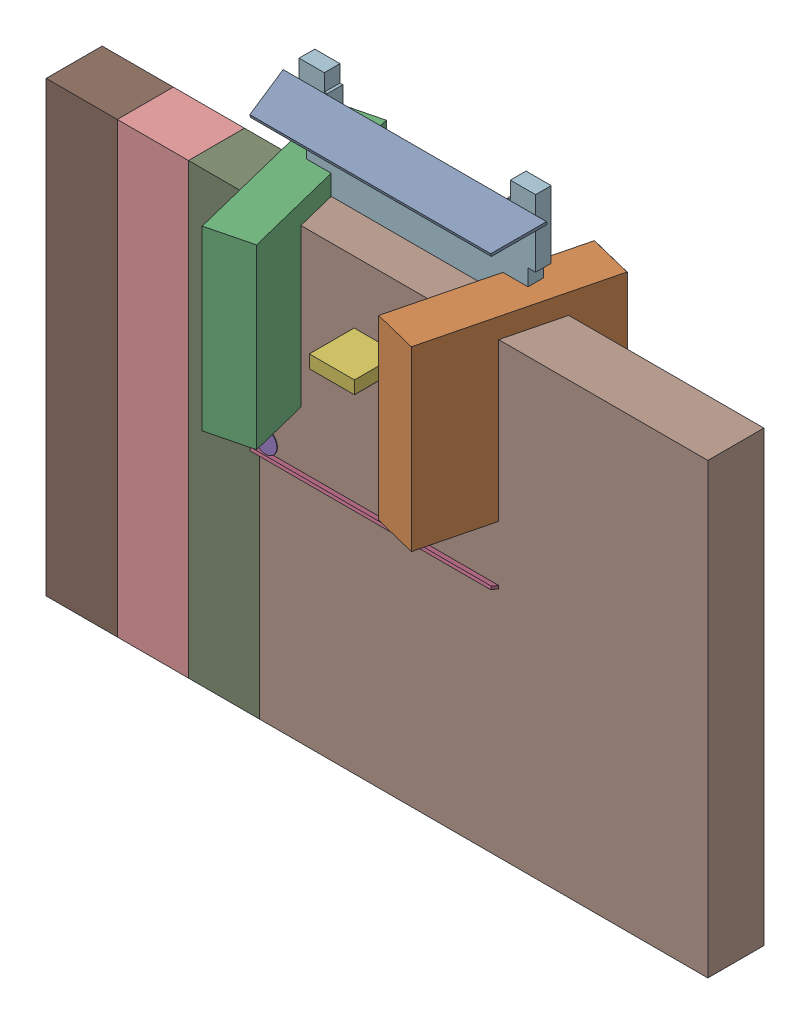
SolidWorks assembly User Library-DFN5x6_SO8FL, configuration 默认. Lengths in mm.
Overall size (11.81 9.85 3.29).
25 component instances, 7 part files, 0 mates.
Components (placement in the parent):
- Free-Models-1: Free-Models [默认] at origin size (11.81 9.85 3.29)
  - SIDE_S-1: SIDE_S [默认] at (1.9 5.4223 0.705) x (1 0 0) z (0 0.970296 0.241922) size (4.7 0.82 0.05)
    - Extruded-1: Extruded [默认] at origin size (4.7 0.82 0.05)
  - SIDE_L-1: SIDE_L [默认] at (4.1508 2.775 0.705) x (0.241922 0 -0.970296) z (-0.970296 0 -0.241922) size (3.19 3.17 0.81)
    - Extruded_2-1: Extruded_2 [默认] at origin size (3.19 3.17 0.81)
  - SIDE_L-1-1: SIDE_L-1 [默认] at (-0.3508 2.775 0.705) x (-0.241922 0 -0.970296) z (0.970296 0 -0.241922) size (3.19 3.17 0.81)
    - Extruded_2-1: Extruded_2 [默认] at origin size (3.19 3.17 0.81)
  - SIDE_S-1-1: SIDE_S-1 [默认] at (1.9 0.1277 0.705) x (-1 0 0) z (0 -0.970296 0.241922) size (4.7 0.82 0.05)
    - Extruded-1: Extruded [默认] at origin size (4.7 0.82 0.05)
  - 587257496-1: 587257496 [默认] at (0.0484 0.4796 1.12) size (0.4 0.4 0.01)
    - Cylinder-1: Cylinder [默认] at origin size (0.4 0.4 0.01)
  - 750905040-1: 750905040 [默认] at (1.9 2.775 1) size (0.8 0.23 0.8)
    - Extruded_3-1: Extruded_3 [默认] at origin size (0.8 0.23 0.8)
  - 266863104-1: 266863104 [默认] at (1.9025 2.775 0.02) size (0.8 1.14 0.8)
    - Extruded_4-1: Extruded_4 [默认] at origin size (0.8 1.14 0.8)
  - 500156144-1: 500156144 [默认] at (3.81 0 0) size (8 8 1)
    - Extruded_5-1: Extruded_5 [默认] at origin size (8 8 1)
  - 500156144-1-1: 500156144-1 [默认] at (2.54 0 0) size (8 8 1)
    - Extruded_5-1: Extruded_5 [默认] at origin size (8 8 1)
  - 500156144-2-1: 500156144-2 [默认] at (1.27 0 0) size (8 8 1)
    - Extruded_5-1: Extruded_5 [默认] at origin size (8 8 1)
  - 500156144-3-1: 500156144-3 [默认] at origin size (8 8 1)
    - Extruded_5-1: Extruded_5 [默认] at origin size (8 8 1)
  - 500160368-1: 500160368 [默认] at (1.905 3.335 0) size (5.15 5.03 0.28)
    - Extruded_6-1: Extruded_6 [默认] at origin size (5.15 5.03 0.28)
